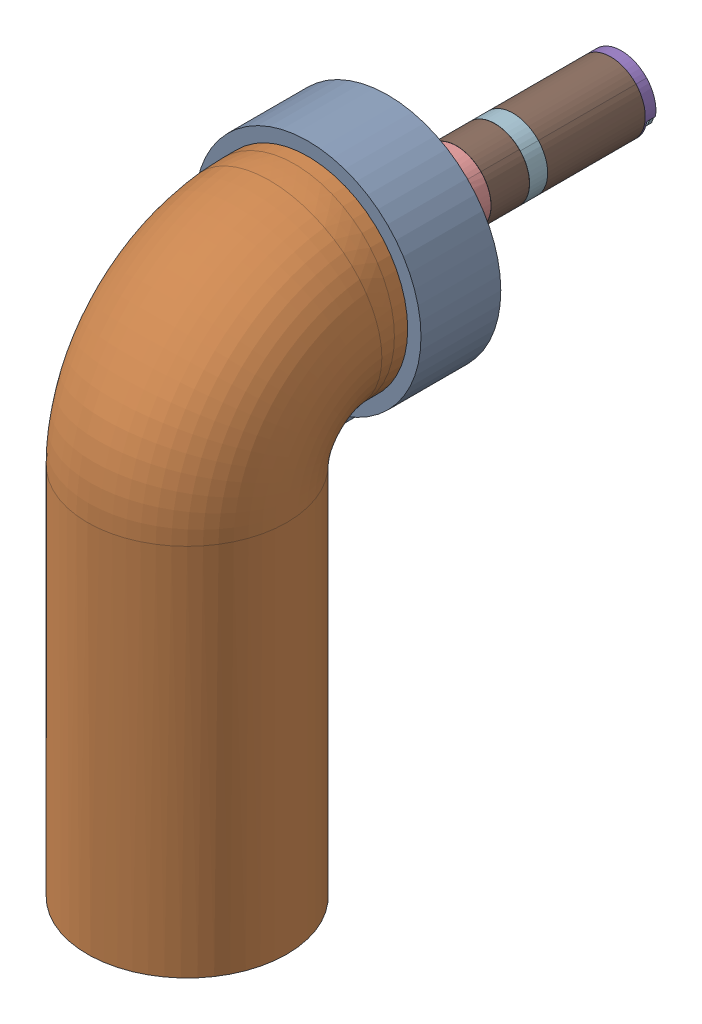
SolidWorks assembly arm_3_assembly, configuration Default. Lengths in mm.
Overall size (170 446.71 401.51).
7 component instances, 7 part files, 12 mates.
Components (placement in the parent):
- rotary_joint-1: rotary_joint [Default] at (-268.6933 361.7149 0) x (0 1 0) z (1 0 0) size (197.58 60 170)
- arm3-1: arm3 [Default] at (-268.6933 361.7149 40) x (0 1 0) z (1 0 0) size (436.71 185.86 150)
- bushing hub-1: bushing hub [9859T718] at (-268.6933 361.7149 60.475) x (0 0 -1) z (1 0 0) size (35.75 63.5 63.5)
- arm ball bearing-1: arm ball bearing [5972K119] at (-268.6933 361.7149 30) x (0.354614 0.935013 0) z (0 0 1) size (52 52 15)
- arm 1 shaft coupler-1: arm 1 shaft coupler [6853N141] at (-268.6933 361.7149 -4.6391) x (1 0 0) z (0 0 -1) size (38.97 38.89 48.13)
- arm 1 motor-1: arm 1 motor [Default] at (-342.135 345.4416 -42.1) x (-0.706748 -0.707465 0) z (0 0 1) size (52 52 172)
- arm 3 shaft-1: arm 3 shaft [Default] at (-268.6933 361.7149 -3.65) x (0 1 0) z (1 0 0) size (20 80 20)
Mates (geometry in assembly coordinates):
- Coincident1: coincident anti-aligned: plane of rotary_joint-1 through (-268.6933 361.7149 40) normal (0 0 1); plane of arm3-1 through (-268.6933 361.7149 40) normal (0 0 -1)
- Concentric2: concentric anti-aligned: cylinder of rotary_joint-1 through (-268.6933 361.7149 60) axis (0 0 -1) radius 26; cylinder of arm3-1 through (-268.6933 361.7149 40) axis (0 0 1) radius 75
- Concentric3: concentric anti-aligned: circle of bushing hub-1; circle of arm 3 shaft-1
- Coincident6: coincident aligned: plane of bushing hub-1 through (-268.6933 361.7149 76.35) normal (0 0 1); plane of arm 3 shaft-1 through (-268.6933 361.7149 76.35) normal (0 0 1)
- Concentric4: concentric aligned: circle of arm ball bearing-1; circle of arm 3 shaft-1
- Concentric5: concentric aligned: circle of rotary_joint-1; circle of arm ball bearing-1
- Distance3: distance = 22.5 mm aligned: plane of arm ball bearing-1 through (-278.7447 365.527 22.5) normal (0 0 -1); plane of rotary_joint-1 through (-268.6933 361.7149 0) normal (0 0 -1)
- Coincident11: coincident aligned: circle of arm3-1; plane of bushing hub-1 through (-268.6933 329.9649 70) normal (0 0 -1)
- Concentric6: concentric anti-aligned: circle of arm 1 shaft coupler-1; circle of arm 1 motor-1
- Coincident12: coincident anti-aligned: plane of arm 1 shaft coupler-1 through (-268.6933 343.2404 -28.65) normal (0 0 -1); plane of arm 1 motor-1 through (-268.6933 361.7149 -28.65) normal (0 0 1)
- Concentric7: concentric aligned: circle of arm 1 shaft coupler-1; circle of arm 3 shaft-1
- Coincident13: coincident anti-aligned: plane of arm 3 shaft-1 through (-268.6933 361.7149 -3.65) normal (0 0 -1); plane of arm 1 motor-1 through (-268.6933 361.7149 -3.65) normal (0 0 1)
